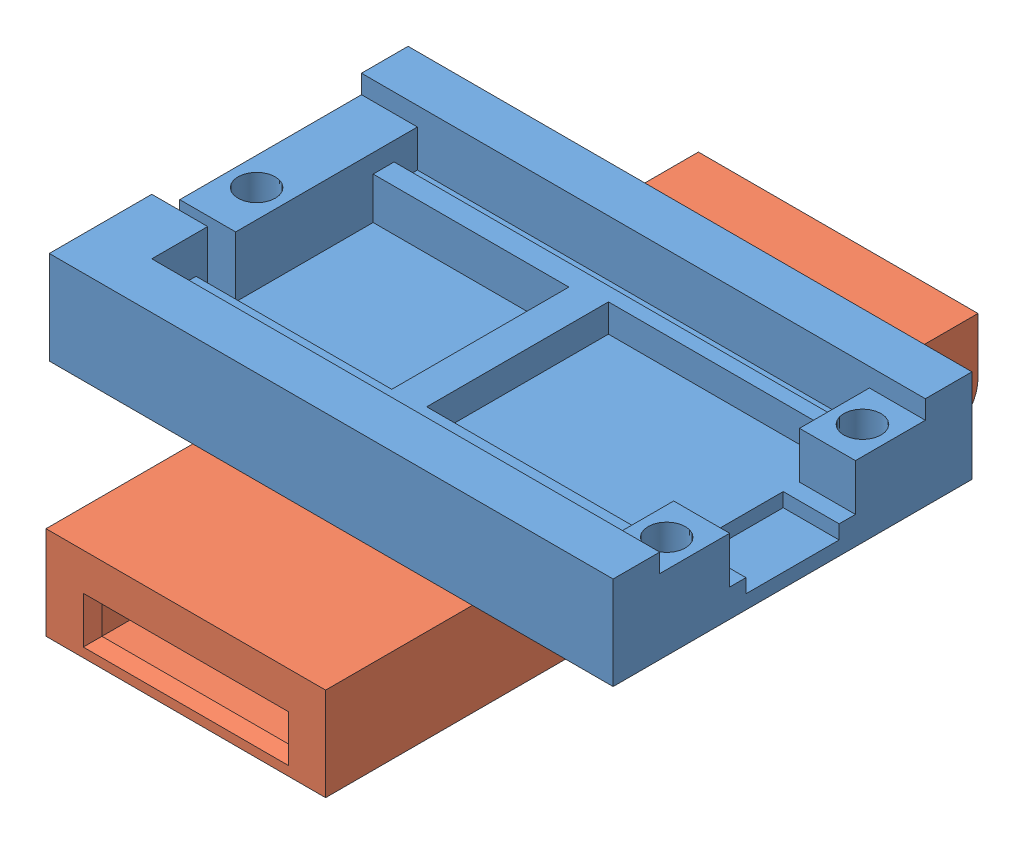
SolidWorks assembly nosilec_esp32, configuration Default. Lengths in mm.
Overall size (60.5 20 70).
2 component instances, 2 part files, 3 mates.
Components (placement in the parent):
- nosilec_esp32-1: nosilec_esp32 [Default] at (21.0017 32.4926 44.0099) size (60.5 10 38.5)
- din_nosilec-1: din_nosilec [Default] at (42.3874 32.4926 79.3413) x (0 0 -1) z (-1 0 0) size (70 10 30)
Mates (geometry in assembly coordinates):
- Coincident1: coincident anti-aligned: plane of nosilec_esp32-1 through (21.0017 32.4926 44.0099) normal (0 -1 0); plane of din_nosilec-1 through (42.3874 32.4926 79.3413) normal (0 1 0)
- Distance1: distance = 15.75 mm aligned: plane of din_nosilec-1 through (42.3874 22.4926 79.3413) normal (0 0 1); plane of nosilec_esp32-1 through (-3.0126 38.4926 63.5913) normal (0 0 1)
- Distance2: distance = 15.4 mm aligned: plane of din_nosilec-1 through (12.3874 32.4926 79.3413) normal (-1 0 0); plane of nosilec_esp32-1 through (-3.0126 38.4926 25.0913) normal (-1 0 0)
